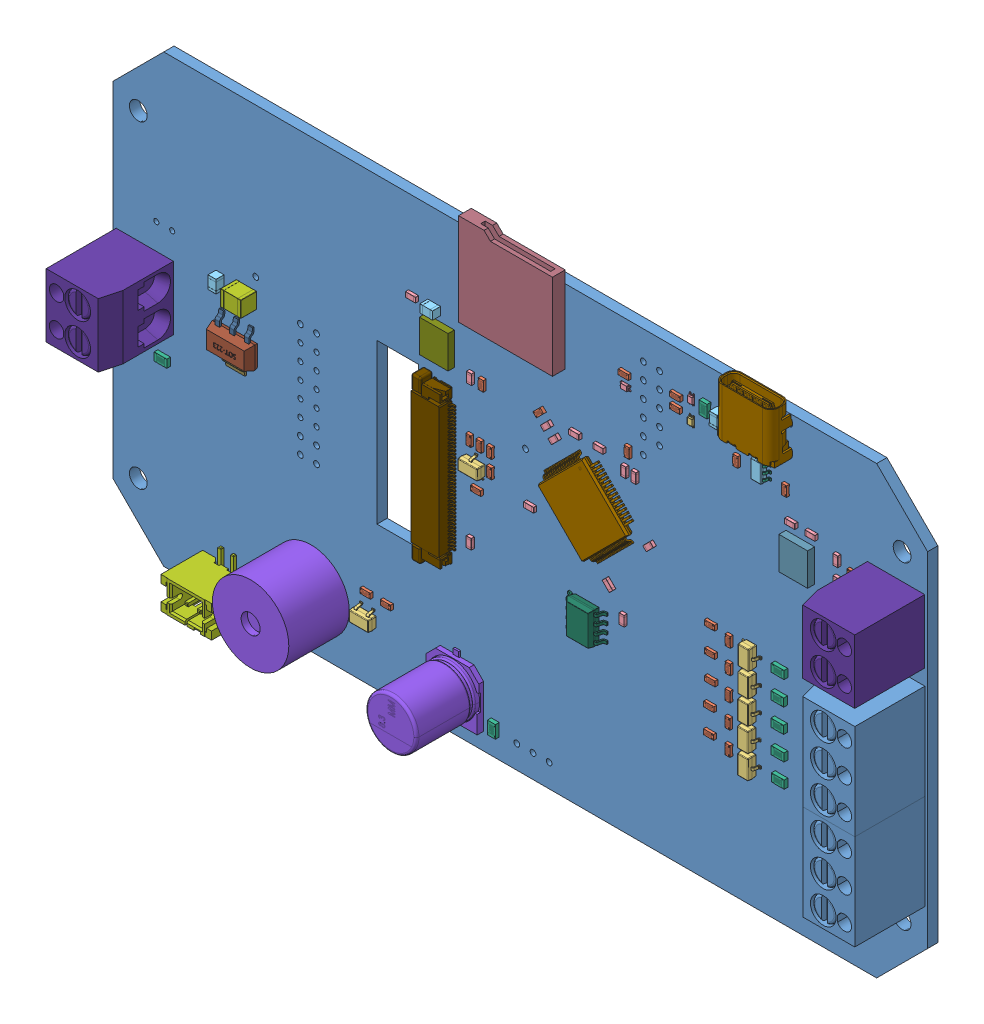
SolidWorks assembly controleo3_clone, configuration Default. Lengths in mm.
Overall size (128 72.88 15.5).
197 component instances, 28 part files, 0 mates.
Components (placement in the parent):
- controleo3_clone.step-1: controleo3_clone.step [Default] at origin size (128 72.88 15.5)
  - Board.step-1: Board.step [Default] at origin size (128 70 1.61)
    - Open CASCADE STEP translator 6.8 1.1.1.step-1: Open CASCADE STEP translator 6.8 1.1.1.step [Default] at (0 0 -1.6118) size (128 70 1.61)
  - R34.step-1: R34.step [Default] at origin size (0.8 1.6 0.45)
    - RES_0603.step-1: RES_0603.step [Default] at (59.14 41.5101 0) x (0 1 0) z (1 0 0) size (1.6 0.45 0.8)
  - R33.step-1: R33.step [Default] at origin size (1.6 0.8 0.45)
    - RES_0603.step-1: RES_0603.step [Default] at (57.4401 35.63 0) x (1 0 0) z (0 -1 0) size (1.6 0.45 0.8)
  - R32.step-1: R32.step [Default] at origin size (0.8 1.6 0.45)
    - RES_0603.step-1: RES_0603.step [Default] at (57.51 41.5401 0) x (0 1 0) z (1 0 0) size (1.6 0.45 0.8)
  - R31.step-1: R31.step [Default] at origin size (0.8 1.6 0.45)
    - RES_0603.step-1: RES_0603.step [Default] at (59.14 38.7401 0) x (0 1 0) z (1 0 0) size (1.6 0.45 0.8)
  - R30.step-1: R30.step [Default] at origin size (0.8 1.6 0.45)
    - RES_0603.step-1: RES_0603.step [Default] at (57.85 50.0301 0) x (0 1 0) z (1 0 0) size (1.6 0.45 0.8)
  - Q2.step-1: Q2.step [Default] at origin size (3.1 3 1.45)
    - SC-59A.step-1: SC-59A.step [Default] at (56.1851 37.0251 0) x (1 0 0) z (0 0 1) size (3.1 3 1.45)
      - Open CASCADE STEP translator 6.8 1.7.1.1.step-1: Open CASCADE STEP translator 6.8 1.7.1.1.step [Default] at origin size (3.1 3 1.45)
      - Open CASCADE STEP translator 6.8 1.7.1.2.step-1: Open CASCADE STEP translator 6.8 1.7.1.2.step [Default] at origin
  - C23.step-1: C23.step [Default] at origin size (0.8 1.6 0.5)
    - CAPC0603_v1.step-1: CAPC0603_v1.step [Default] at (56.3999 27.6301 0) x (0 1 0) z (0 0 1) size (1.6 0.8 0.5)
  - C22.step-1: C22.step [Default] at origin size (2 1.27 1.27)
    - 0805_cap.step-1: 0805_cap.step [Default] at (50.4801 57.117 0.62) x (-1 0 0) z (0 0 1) size (2 1.27 1.27)
  - C4.step-1: C4.step [Default] at origin size (1.6 0.8 0.5)
    - CAPC0603_v1.step-1: CAPC0603_v1.step [Default] at (47.2501 56.4801 0) x (1 0 0) z (0 0 1) size (1.6 0.8 0.5)
  - C7.step-1: C7.step [Default] at origin size (0.8 1.6 0.5)
    - CAPC0603_v1.step-1: CAPC0603_v1.step [Default] at (56.4399 50.0401 0) x (0 1 0) z (0 0 1) size (1.6 0.8 0.5)
  - R29.step-1: R29.step [Default] at origin size (2 1.25 0.6)
    - 0805_resistor.step-1: 0805_resistor.step [Default] at (8.0799 27.775 0) x (-1 0 0) z (0 1 0) size (2 0.6 1.25)
  - R28.step-1: R28.step [Default] at origin size (1.6 0.8 0.45)
    - RES_0603.step-1: RES_0603.step [Default] at (94.0199 19.95 0) x (-1 0 0) z (0 1 0) size (1.6 0.45 0.8)
  - R27.step-1: R27.step [Default] at origin size (0.8 1.6 0.45)
    - RES_0603.step-1: RES_0603.step [Default] at (98.63 59.6599 0) x (0 -1 0) z (-1 0 0) size (1.6 0.45 0.8)
  - R26.step-1: R26.step [Default] at origin size (0.8 1.6 0.45)
    - RES_0603.step-1: RES_0603.step [Default] at (106.27 59.5199 0) x (0 -1 0) z (-1 0 0) size (1.6 0.45 0.8)
  - R25.step-1: R25.step [Default] at origin size (1.6 0.8 0.45)
    - RES_0603.step-1: RES_0603.step [Default] at (94.0699 23.75 0) x (-1 0 0) z (0 1 0) size (1.6 0.45 0.8)
  - R18.step-1: R18.step [Default] at origin size (1.6 0.8 0.45)
    - RES_0603.step-1: RES_0603.step [Default] at (94.2399 27.33 0) x (-1 0 0) z (0 1 0) size (1.6 0.45 0.8)
  - R17.step-1: R17.step [Default] at origin size (1.6 0.8 0.45)
    - RES_0603.step-1: RES_0603.step [Default] at (94.2099 31.05 0) x (-1 0 0) z (0 1 0) size (1.6 0.45 0.8)
  - R16.step-1: R16.step [Default] at origin size (1.6 0.8 0.45)
    - RES_0603.step-1: RES_0603.step [Default] at (94.1799 34.89 0) x (-1 0 0) z (0 1 0) size (1.6 0.45 0.8)
  - P9.step-1: P9.step [Default] at origin size (7.95 7 6.74)
    - JST-B2B-PH-SM4-TB.step-1: JST-B2B-PH-SM4-TB.step [Default] at (14.7349 2.8799 0) x (1 0 0) z (0 -1 0) size (7.95 6.74 7)
  - C12.step-1: C12.step [Default] at origin size (8.3 9.9 10.5)
    - CAP_ALUM_8_3mm.step-1: CAP_ALUM_8_3mm.step [Default] at (54.1901 6.9299 0) x (0 -1 0) z (-1 0 0) size (9.9 10.5 8.3)
  - U2.step-1: U2.step [Default] at origin size (15.1 15.1 1.2)
    - 5887058672.step-1: 5887058672.step [Default] at (74.88 41.62 0) x (0.707107 -0.707107 0) z (0 0 1) size (11.99 11.99 1.2)
  - U1.step-1: U1.step [Default] at origin size (6.7 7.2 1.9)
    - SOT-223-2.step-1: SOT-223-2.step [Default] at (19.1599 36.0099 0.5) x (-1 0 0) z (0 0 1) size (6.7 7.2 1.9)
      - User_Library-SOT-223-2_PIN_SOT-223_2_1.step-1: User_Library-SOT-223-2_PIN_SOT-223_2_1.step [Default] at (-0.7519 -1.8225 0.05) x (0 0 -1) z (1 0 0) size (0.9 1.94 0.7)
      - User_Library-SOT-223-2_SOT-223_1.step-1: User_Library-SOT-223-2_SOT-223_1.step [Default] at (-0.3519 -0.0725 0.05) size (6.7 3.5 1.8)
      - User_Library-SOT-223-2_PIN_SOT-223_2_1.step-2: User_Library-SOT-223-2_PIN_SOT-223_2_1.step [Default] at (-3.0519 -1.8225 0.05) x (0 0 -1) z (1 0 0) size (0.9 1.94 0.7)
      - User_Library-SOT-223-2_PIN_SOT-223_1.step-1: User_Library-SOT-223-2_PIN_SOT-223_1.step [Default] at (1.1481 1.6775 0.05) x (0 0 -1) z (-1 0 0) size (0.9 1.94 3)
      - User_Library-SOT-223-2_PIN_SOT-223_2_1.step-3: User_Library-SOT-223-2_PIN_SOT-223_2_1.step [Default] at (1.5481 -1.8225 0.05) x (0 0 -1) z (1 0 0) size (0.9 1.94 0.7)
  - SD1.step-1: SD1.step [Default] at origin size (14.75 14.5 2.65)
    - SD-Card_socket.step-1: SD-Card_socket.step [Default] at (63.6949 65.6349 0) x (-1 0 0) z (0 1 0) size (14.75 2.65 14.5)
  - R24.step-1: R24.step [Default] at origin size (1.6 0.8 0.45)
    - RES_0603.step-1: RES_0603.step [Default] at (116.5899 53 0) x (-1 0 0) z (0 1 0) size (1.6 0.45 0.8)
  - R23.step-1: R23.step [Default] at origin size (1.6 0.8 0.45)
    - RES_0603.step-1: RES_0603.step [Default] at (116.6299 48.03 0) x (-1 0 0) z (0 1 0) size (1.6 0.45 0.8)
  - R22.step-1: R22.step [Default] at origin size (1.6 0.8 0.45)
    - RES_0603.step-1: RES_0603.step [Default] at (40.0901 12.99 0) x (1 0 0) z (0 -1 0) size (1.6 0.45 0.8)
  - R21.step-1: R21.step [Default] at origin size (1.6 0.8 0.45)
    - RES_0603.step-1: RES_0603.step [Default] at (43.2701 12.97 0) x (1 0 0) z (0 -1 0) size (1.6 0.45 0.8)
  - R20.step-1: R20.step [Default] at origin size (0.8 1.6 0.45)
    - RES_0603.step-1: RES_0603.step [Default] at (96.61 19.7201 0) x (0 1 0) z (1 0 0) size (1.6 0.45 0.8)
  - R19.step-1: R19.step [Default] at origin size (2 1.25 0.6)
    - 0805_resistor.step-1: 0805_resistor.step [Default] at (105.0601 20.245 0) x (1 0 0) z (0 -1 0) size (2 0.6 1.25)
  - R15.step-1: R15.step [Default] at origin size (0.8 1.6 0.45)
    - RES_0603.step-1: RES_0603.step [Default] at (96.5899 23.4101 0) x (0 1 0) z (1 0 0) size (1.6 0.45 0.8)
  - R14.step-1: R14.step [Default] at origin size (0.8 1.6 0.45)
    - RES_0603.step-1: RES_0603.step [Default] at (56.7 41.5199 0) x (0 -1 0) z (-1 0 0) size (1.6 0.45 0.8)
  - R13.step-1: R13.step [Default] at origin size (2 1.25 0.6)
    - 0805_resistor.step-1: 0805_resistor.step [Default] at (105.0401 23.935 0) x (1 0 0) z (0 -1 0) size (2 0.6 1.25)
  - R12.step-1: R12.step [Default] at origin size (1.25 2 0.6)
    - 0805_resistor.step-1: 0805_resistor.step [Default] at (60.695 4.1199 0) x (0 -1 0) z (-1 0 0) size (2 0.6 1.25)
  - R11.step-1: R11.step [Default] at origin size (0.8 1.6 0.45)
    - RES_0603.step-1: RES_0603.step [Default] at (96.6199 27.1301 0) x (0 1 0) z (1 0 0) size (1.6 0.45 0.8)
  - R10.step-1: R10.step [Default] at origin size (0.8 1.6 0.45)
    - RES_0603.step-1: RES_0603.step [Default] at (81.57 52.3399 0) x (0 -1 0) z (-1 0 0) size (1.6 0.45 0.8)
  - R9.step-1: R9.step [Default] at origin size (2 1.25 0.6)
    - 0805_resistor.step-1: 0805_resistor.step [Default] at (104.9701 27.655 0) x (1 0 0) z (0 -1 0) size (2 0.6 1.25)
  - R8.step-1: R8.step [Default] at origin size (0.8 1.6 0.45)
    - RES_0603.step-1: RES_0603.step [Default] at (96.65 30.8401 0) x (0 1 0) z (1 0 0) size (1.6 0.45 0.8)
  - R7.step-1: R7.step [Default] at origin size (2 1.25 0.6)
    - 0805_resistor.step-1: 0805_resistor.step [Default] at (105.0001 31.385 0) x (1 0 0) z (0 -1 0) size (2 0.6 1.25)
  - R6.step-1: R6.step [Default] at origin size (0.8 1.6 0.45)
    - RES_0603.step-1: RES_0603.step [Default] at (96.64 34.5801 0) x (0 1 0) z (1 0 0) size (1.6 0.45 0.8)
  - R5.step-1: R5.step [Default] at origin size (2 1.25 0.6)
    - 0805_resistor.step-1: 0805_resistor.step [Default] at (105.0401 35.155 0) x (1 0 0) z (0 -1 0) size (2 0.6 1.25)
  - R4.step-1: R4.step [Default] at origin size (1.6 0.8 0.45)
    - RES_0603.step-1: RES_0603.step [Default] at (88.7101 62.44 0) x (1 0 0) z (0 -1 0) size (1.6 0.45 0.8)
  - R3.step-1: R3.step [Default] at origin size (1.6 0.8 0.45)
    - RES_0603.step-1: RES_0603.step [Default] at (88.7401 64.09 0) x (1 0 0) z (0 -1 0) size (1.6 0.45 0.8)
  - R2.step-1: R2.step [Default] at origin size (1.6 0.8 0.45)
    - RES_0603.step-1: RES_0603.step [Default] at (80.6399 62.22 0) x (-1 0 0) z (0 1 0) size (1.6 0.45 0.8)
  - R1.step-1: R1.step [Default] at origin size (1.25 2 0.6)
    - 0805_resistor.step-1: 0805_resistor.step [Default] at (92.695 64.3101 0) x (0 1 0) z (1 0 0) size (2 0.6 1.25)
  - Q5.step-1: Q5.step [Default] at origin size (4.5 5.1 1.1)
    - 5908523488.step-1: 5908523488.step [Default] at (108.1 51.34 0.1) size (4.5 5.1 1.1)
      - Extruded.step-1: Extruded.step [Default] at origin size (4.5 5.1 1.1)
  - Q4.step-1: Q4.step [Default] at origin size (6.41 5 2.14)
    - SOIC08_narrow.step-1: SOIC08_narrow.step [Default] at (74.7801 26.5201 0) x (0 1 0) z (0 0 1) size (5 6.41 2.14)
  - Q3.step-1: Q3.step [Default] at origin size (3.1 3 1.45)
    - SC-59A.step-1: SC-59A.step [Default] at (40.9849 10.6549 0) x (-1 0 0) z (0 0 1) size (3.1 3 1.45)
      - Open CASCADE STEP translator 6.8 1.7.1.1.step-1: Open CASCADE STEP translator 6.8 1.7.1.1.step [Default] at origin size (3.1 3 1.45)
      - Open CASCADE STEP translator 6.8 1.7.1.2.step-1: Open CASCADE STEP translator 6.8 1.7.1.2.step [Default] at origin
  - Q1.step-1: Q1.step [Default] at origin size (4.5 5.1 1)
    - 5908523328.step-1: 5908523328.step [Default] at (51.51 52.55 0.1) size (4.5 5.1 1)
      - Extruded-0.step-1: Extruded-0.step [Default] at origin size (4.5 5.1 1)
  - P8.step-1: P8.step [Default] at origin size (9 10 15.5)
    - 237-102.step-1: 237-102.step [Default] at (122.7551 45.9501 0) x (-1 0 0) z (0 1 0) size (9 15.5 10)
  - P5.step-1: P5.step [Default] at origin size (5.11 25.43 2.06)
    - c-4-1734839-0-c-3d.step-1: c-4-1734839-0-c-3d.step [Default] at (48.85 35.0101 1) x (0 -1 0) z (-1 0 0) size (25.43 2.06 5.11)
  - P4.step-1: P4.step [Default] at origin size (9 15 15.5)
    - 237-103.step-1: 237-103.step [Default] at (122.7601 13.4951 0) x (-1 0 0) z (0 1 0) size (9 15.5 15)
  - P2.step-1: P2.step [Default] at origin size (9 15 15.5)
    - 237-103.step-1: 237-103.step [Default] at (122.7701 28.4951 0) x (-1 0 0) z (0 1 0) size (9 15.5 15)
  - P1.step-1: P1.step [Default] at origin size (9 10 15.5)
    - 237-102.step-1: 237-102.step [Default] at (5.3249 42.2799 0) x (1 0 0) z (0 -1 0) size (9 15.5 10)
  - NF5.step-1: NF5.step [Default] at origin size (3 3.1 1.45)
    - SC-59A.step-1: SC-59A.step [Default] at (98.9851 20.5449 0) x (0 -1 0) z (0 0 1) size (3.1 3 1.45)
      - Open CASCADE STEP translator 6.8 1.7.1.1.step-1: Open CASCADE STEP translator 6.8 1.7.1.1.step [Default] at origin size (3.1 3 1.45)
      - Open CASCADE STEP translator 6.8 1.7.1.2.step-1: Open CASCADE STEP translator 6.8 1.7.1.2.step [Default] at origin
  - NF4.step-1: NF4.step [Default] at origin size (3 3.1 1.45)
    - SC-59A.step-1: SC-59A.step [Default] at (98.9651 24.2349 0) x (0 -1 0) z (0 0 1) size (3.1 3 1.45)
      - Open CASCADE STEP translator 6.8 1.7.1.1.step-1: Open CASCADE STEP translator 6.8 1.7.1.1.step [Default] at origin size (3.1 3 1.45)
      - Open CASCADE STEP translator 6.8 1.7.1.2.step-1: Open CASCADE STEP translator 6.8 1.7.1.2.step [Default] at origin
  - NF3.step-1: NF3.step [Default] at origin size (3 3.1 1.45)
    - SC-59A.step-1: SC-59A.step [Default] at (98.9951 27.9549 0) x (0 -1 0) z (0 0 1) size (3.1 3 1.45)
      - Open CASCADE STEP translator 6.8 1.7.1.1.step-1: Open CASCADE STEP translator 6.8 1.7.1.1.step [Default] at origin size (3.1 3 1.45)
      - Open CASCADE STEP translator 6.8 1.7.1.2.step-1: Open CASCADE STEP translator 6.8 1.7.1.2.step [Default] at origin
  - NF2.step-1: NF2.step [Default] at origin size (3 3.1 1.45)
    - SC-59A.step-1: SC-59A.step [Default] at (99.0251 31.6849 0) x (0 -1 0) z (0 0 1) size (3.1 3 1.45)
      - Open CASCADE STEP translator 6.8 1.7.1.1.step-1: Open CASCADE STEP translator 6.8 1.7.1.1.step [Default] at origin size (3.1 3 1.45)
      - Open CASCADE STEP translator 6.8 1.7.1.2.step-1: Open CASCADE STEP translator 6.8 1.7.1.2.step [Default] at origin
  - NF1.step-1: NF1.step [Default] at origin size (3 3.1 1.45)
    - SC-59A.step-1: SC-59A.step [Default] at (99.0651 35.4549 0) x (0 -1 0) z (0 0 1) size (3.1 3 1.45)
      - Open CASCADE STEP translator 6.8 1.7.1.1.step-1: Open CASCADE STEP translator 6.8 1.7.1.1.step [Default] at origin size (3.1 3 1.45)
      - Open CASCADE STEP translator 6.8 1.7.1.2.step-1: Open CASCADE STEP translator 6.8 1.7.1.2.step [Default] at origin
  - FB1.step-1: FB1.step [Default] at origin size (1.7 1.7 0.45)
    - 0603_resistor.step-1: 0603_resistor.step [Default] at (67.5629 50.4872 0) x (-0.707107 -0.707107 0) z (-0.707107 0.707107 0) size (1.6 0.45 0.8)
  - D6.step-1: D6.step [Default] at origin size (0.81 1.61 0.4)
    - LED_Blue_SMD_0603_W_rth_150060BS55040.step-1: LED_Blue_SMD_0603_W_rth_150060BS55040.step [Default] at (91.0101 61.37 0) x (0 -1 0) z (0 0 1) size (1.6 0.81 0.4)
  - D5.step-1: D5.step [Default] at origin size (0.81 1.61 0.4)
    - LED_Red_SMD_0603_W_rth_150060SS55040.step-1: LED_Red_SMD_0603_W_rth_150060SS55040.step [Default] at (91.0199 64.34 0) x (0 1 0) z (0 0 1) size (1.6 0.81 0.4)
  - D3.step-1: D3.step [Default] at origin size (2.84 2.93 1.12)
    - sot-23-6.step-1: sot-23-6.step [Default] at (102.0701 60.5099 0.8128) x (0 -1 0) z (-1 0 0) size (2.93 1.12 2.84)
      - BODY_MF06A.step-1: BODY_MF06A.step [Default] at origin size (2.93 1.02 1.61)
      - LEAD_MF06A.step-1: LEAD_MF06A.step [Default] at (0.9525 -0.6604 0.9652) size (0.37 0.86 0.62)
      - LEAD_MF06A.step-2: LEAD_MF06A.step [Default] at (0 -0.6604 0.9652) size (0.37 0.86 0.62)
      - LEAD_MF06A.step-3: LEAD_MF06A.step [Default] at (-0.9525 -0.6604 0.9652) size (0.37 0.86 0.62)
      - LEAD_MF06A.step-4: LEAD_MF06A.step [Default] at (0.9525 -0.6604 -0.9652) x (-1 0 0) z (0 0 -1) size (0.37 0.86 0.62)
      - LEAD_MF06A.step-5: LEAD_MF06A.step [Default] at (0 -0.6604 -0.9652) x (-1 0 0) z (0 0 -1) size (0.37 0.86 0.62)
      - LEAD_MF06A.step-6: LEAD_MF06A.step [Default] at (-0.9525 -0.6604 -0.9652) x (-1 0 0) z (0 0 -1) size (0.37 0.86 0.62)
  - D1.step-1: D1.step [Default] at origin size (1.61 0.81 0.4)
    - LED_Red_SMD_0603_W_rth_150060SS55040.step-1: LED_Red_SMD_0603_W_rth_150060SS55040.step [Default] at (80.64 60.8701 0) x (1 0 0) z (0 0 1) size (1.6 0.81 0.4)
  - C21.step-1: C21.step [Default] at origin size (1.6 0.8 0.5)
    - CAPC0603_v1.step-1: CAPC0603_v1.step [Default] at (106.8301 55.4501 0) x (1 0 0) z (0 0 1) size (1.6 0.8 0.5)
  - C20.step-1: C20.step [Default] at origin size (0.8 1.6 0.5)
    - CAPC0603_v1.step-1: CAPC0603_v1.step [Default] at (113.9901 54.0299 0) x (0 -1 0) z (0 0 1) size (1.6 0.8 0.5)
  - C19.step-1: C19.step [Default] at origin size (1.6 0.8 0.5)
    - CAPC0603_v1.step-1: CAPC0603_v1.step [Default] at (109.9999 55.4399 0) x (-1 0 0) z (0 0 1) size (1.6 0.8 0.5)
  - C18.step-1: C18.step [Default] at origin size (0.8 1.6 0.5)
    - CAPC0603_v1.step-1: CAPC0603_v1.step [Default] at (114.0001 50.9999 0) x (0 -1 0) z (0 0 1) size (1.6 0.8 0.5)
  - C17.step-1: C17.step [Default] at origin size (0.8 1.6 0.5)
    - CAPC0603_v1.step-1: CAPC0603_v1.step [Default] at (114.0001 47.8199 0) x (0 -1 0) z (0 0 1) size (1.6 0.8 0.5)
  - C16.step-1: C16.step [Default] at origin size (0.8 1.6 0.5)
    - CAPC0603_v1.step-1: CAPC0603_v1.step [Default] at (80.4199 29.1701 0) x (0 1 0) z (0 0 1) size (1.6 0.8 0.5)
  - C15.step-1: C15.step [Default] at origin size (1.7 1.7 0.5)
    - CAPC0603_v1.step-1: CAPC0603_v1.step [Default] at (78.1999 32.76 0) x (-0.707107 0.707107 0) z (0 0 1) size (1.6 0.8 0.5)
  - C14.step-1: C14.step [Default] at origin size (1.6 0.8 0.5)
    - CAPC0603_v1.step-1: CAPC0603_v1.step [Default] at (65.8101 37.1701 0) x (1 0 0) z (0 0 1) size (1.6 0.8 0.5)
  - C13.step-1: C13.step [Default] at origin size (1.7 1.7 0.5)
    - CAPC0603_v1.step-1: CAPC0603_v1.step [Default] at (84.58 41.2199 0) x (-0.707107 -0.707107 0) z (0 0 1) size (1.6 0.8 0.5)
  - C11.step-1: C11.step [Default] at origin size (0.8 1.6 0.5)
    - CAPC0603_v1.step-1: CAPC0603_v1.step [Default] at (82.2699 49.5001 0) x (0 1 0) z (0 0 1) size (1.6 0.8 0.5)
  - C10.step-1: C10.step [Default] at origin size (1.7 1.7 0.5)
    - CAPC0603_v1.step-1: CAPC0603_v1.step [Default] at (68.48 49.5499 0) x (-0.707107 -0.707107 0) z (0 0 1) size (1.6 0.8 0.5)
  - C9.step-1: C9.step [Default] at origin size (1.7 1.7 0.5)
    - CAPC0603_v1.step-1: CAPC0603_v1.step [Default] at (69.68 48.3299 0) x (-0.707107 -0.707107 0) z (0 0 1) size (1.6 0.8 0.5)
  - C8.step-1: C8.step [Default] at origin size (0.8 1.6 0.5)
    - CAPC0603_v1.step-1: CAPC0603_v1.step [Default] at (80.6799 49.4901 0) x (0 1 0) z (0 0 1) size (1.6 0.8 0.5)
  - C6.step-1: C6.step [Default] at origin size (1.6 0.8 0.5)
    - CAPC0603_v1.step-1: CAPC0603_v1.step [Default] at (72.8999 50.6199 0) x (-1 0 0) z (0 0 1) size (1.6 0.8 0.5)
  - C5.step-1: C5.step [Default] at origin size (1.6 0.8 0.5)
    - CAPC0603_v1.step-1: CAPC0603_v1.step [Default] at (76.6901 50.6101 0) x (1 0 0) z (0 0 1) size (1.6 0.8 0.5)
  - C3.step-1: C3.step [Default] at origin size (3.2 2.5 2.5)
    - CAP_1210-2.5mm.step-1: CAP_1210-2.5mm.step [Default] at (21.0099 43.5101 0) x (-1 0 0) z (0 1 0) size (3.2 2.5 2.5)
  - C2.step-1: C2.step [Default] at origin size (1.27 2 1.27)
    - 0805_cap.step-1: 0805_cap.step [Default] at (16.193 43.4101 0.62) x (0 -1 0) z (0 0 1) size (2 1.27 1.27)
  - C1.step-1: C1.step [Default] at origin size (1.27 2 1.27)
    - 0805_cap.step-1: 0805_cap.step [Default] at (96.207 64.2599 0.62) x (0 1 0) z (0 0 1) size (2 1.27 1.27)
  - B1.step-1: B1.step [Default] at origin size (12 12 12.1)
    - HCM1206X.step-1: HCM1206X.step [Default] at (31.1449 8.5099 0) x (-1 0 0) z (0 0 1) size (12 12 12.1)
  - Free-Models.step-1: Free-Models.step [Default] at origin size (8.95 8.1 3.76)
    - c-2345986-1-1-3d.step-1: c-2345986-1-1-3d.step [Default] at (102.07 71.82 1.6) x (-1 0 0) z (0 1 0) size (8.95 3.76 8.1)
